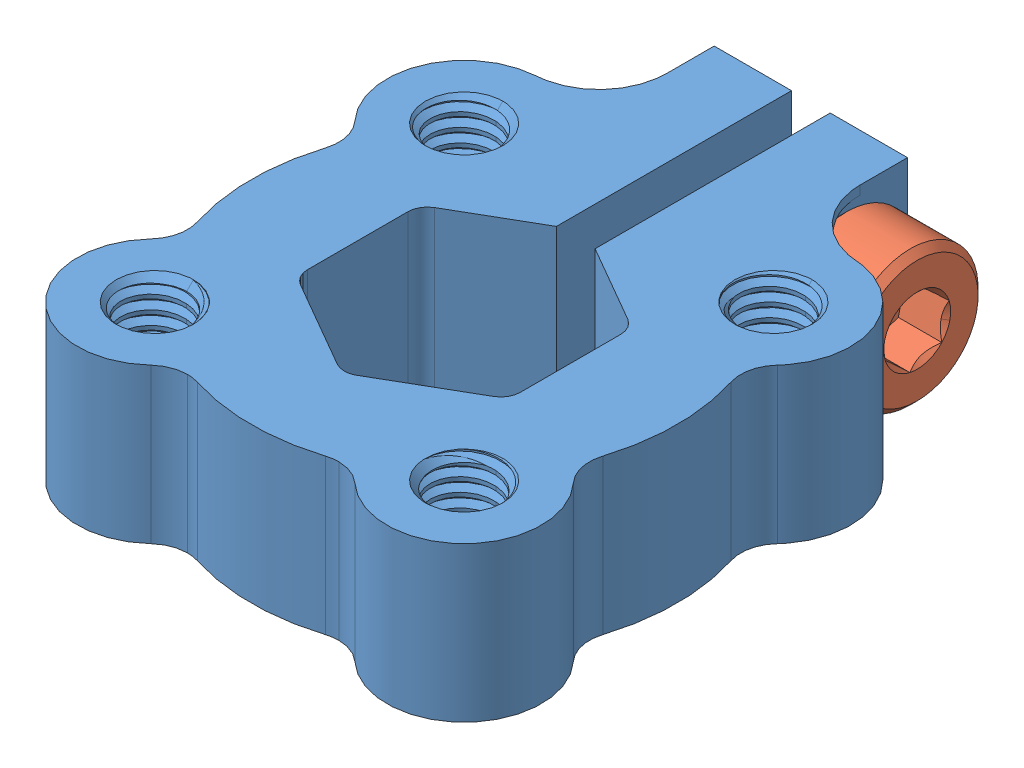
SolidWorks assembly 12mm REX Clamping Hub 1301-0016-4012, configuration Default. Lengths in mm.
Overall size (24 9.18 30.61).
2 component instances, 2 part files, 0 mates.
Components (placement in the parent):
- 1301-0016-4012.STEP-1: 1301-0016-4012.STEP [Default] at (3.0606 3.416 -4.1107) size (24 9 29.94)
- 2800-0004-0010_90128A207.STEP-1: 2800-0004-0010_90128A207.STEP [Default] at (-1.9394 8.416 -18.546) x (0 0.216842 0.976207) z (-1 0 0) size (7 7 14.01)
